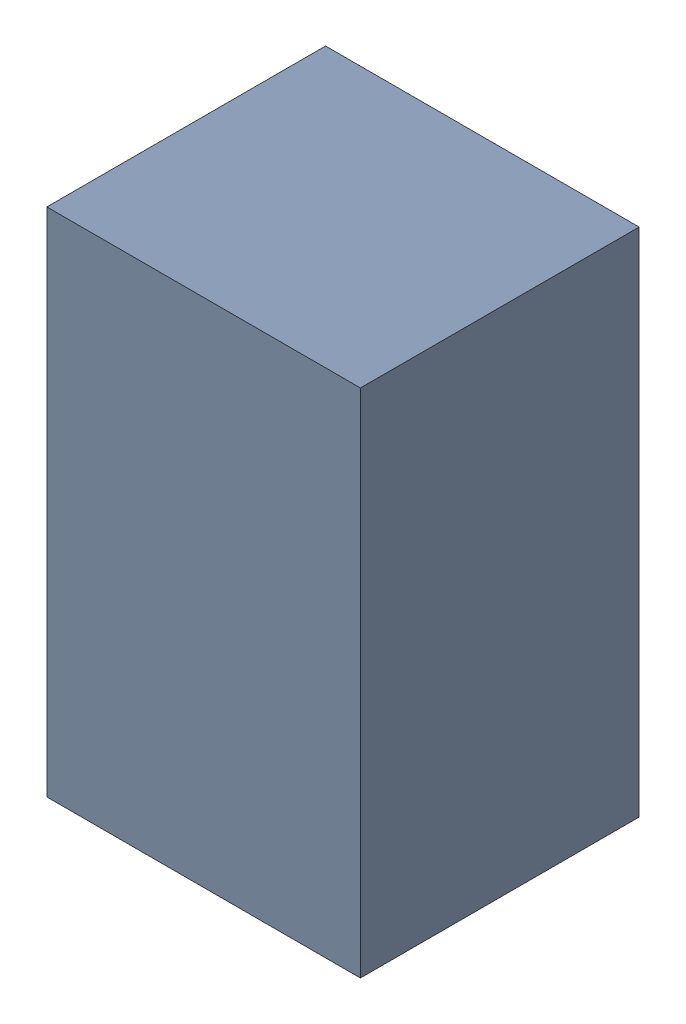
SolidWorks assembly C4, configuration Default. Lengths in mm.
Overall size (1.35 2.2 1.2).
2 component instances, 1 part files, 0 mates.
Components (placement in the parent):
- 407985568-1: 407985568 [Default] at (16.51 61.722 0.0127) size (1.35 2.2 1.2)
  - Extruded_3-1: Extruded_3 [Default] at origin size (1.35 2.2 1.2)
